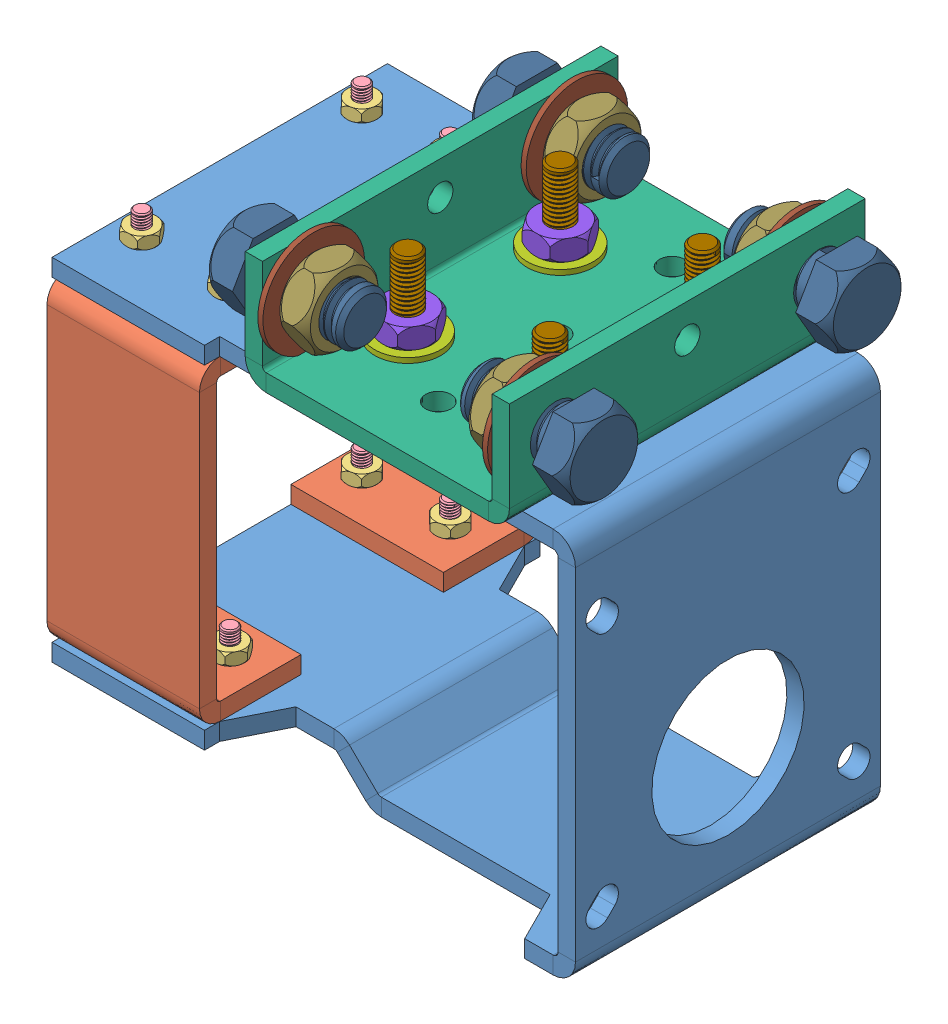
SolidWorks assembly Motor Hub Asm, configuration Default. Lengths in mm.
Overall size (108.85 123.96 126.02).
72 component instances, 12 part files, 10 mates.
Components (placement in the parent):
- Main Motor Flange-1: Main Motor Flange [Default] at (107.3541 101.0612 120.121) x (-1 0 0) z (0 0 -1) size (100 80 66)
- Side Flange x2-1: Side Flange x2 [Default] at (37.3541 66.5612 124.121) x (0 0 1) z (-1 0 0) size (20 62.2 30)
- Screw 3mm total Asm-1: Screw 3mm total Asm [Default] at (21.6788 105.6065 99.6182) x (0.996489 0 0.083719) z (-0.083719 0 0.996489) size (8.57 15.29 8.76)
  - Nut 3 mm-1: Nut 3 mm [Default] at (-6.9703 -2.6351 12.8014) x (0.355877 0 -0.934533) z (0.934533 0 0.355877) size (6.87 2.69 6.56)
  - Screw 3mm-1: Screw 3mm [Default] at (-6.97 -14.6573 12.8027) x (0 0 -1) z (-1 0 0) size (6 15.29 6)
  - Ross 3 mm-1: Ross 3 mm [Default] at (-6.9707 -11.1453 12.802) size (7.8 0.6 7.8)
- Screw 3mm total Asm-2: Screw 3mm total Asm [Default] at (16.5317 105.6065 110.4602) x (-0.395991 0 -0.918254) z (0.918254 0 -0.395991) size (8.57 15.29 8.76)
  - Nut 3 mm-1: Nut 3 mm [Default] at (-6.9703 -2.6351 12.8014) x (0.355877 0 -0.934533) z (0.934533 0 0.355877) size (6.87 2.69 6.56)
  - Screw 3mm-1: Screw 3mm [Default] at (-6.97 -14.6573 12.8027) x (0 0 -1) z (-1 0 0) size (6 15.29 6)
  - Ross 3 mm-1: Ross 3 mm [Default] at (-6.9707 -11.1453 12.802) size (7.8 0.6 7.8)
- Screw 3mm total Asm-13: Screw 3mm total Asm [Default] at (40.0426 105.6065 79.9207) x (-0.395991 0 0.918254) z (-0.918254 0 -0.395991) size (8.57 15.29 8.76)
  - Nut 3 mm-1: Nut 3 mm [Default] at (-6.9703 -2.6351 12.8014) x (0.355877 0 -0.934533) z (0.934533 0 0.355877) size (6.87 2.69 6.56)
  - Screw 3mm-1: Screw 3mm [Default] at (-6.97 -14.6573 12.8027) x (0 0 -1) z (-1 0 0) size (6 15.29 6)
  - Ross 3 mm-1: Ross 3 mm [Default] at (-6.9707 -11.1453 12.802) size (7.8 0.6 7.8)
- Screw 3mm total Asm-15: Screw 3mm total Asm [Default] at (19.5352 105.6065 55.1098) x (0.996489 0 -0.083719) z (0.083719 0 0.996489) size (8.57 15.29 8.76)
  - Nut 3 mm-1: Nut 3 mm [Default] at (-6.9703 -2.6351 12.8014) x (0.355877 0 -0.934533) z (0.934533 0 0.355877) size (6.87 2.69 6.56)
  - Screw 3mm-1: Screw 3mm [Default] at (-6.97 -14.6573 12.8027) x (0 0 -1) z (-1 0 0) size (6 15.29 6)
  - Ross 3 mm-1: Ross 3 mm [Default] at (-6.9707 -11.1453 12.802) size (7.8 0.6 7.8)
- Side Flange x2-2: Side Flange x2 [Default] at (7.3541 66.5612 56.121) x (0 0 -1) z (1 0 0) size (20 62.2 30)
- Upper Flange-1: Upper Flange [Default] at (73.3541 101.0612 55.121) x (0 -1 0) z (0 0 1) size (22 52 70)
- Screw 3mm total Asm-19: Screw 3mm total Asm [Default] at (16.5317 43.4065 110.4602) x (-0.395991 0 -0.918254) z (0.918254 0 -0.395991) size (8.57 15.29 8.76)
  - Nut 3 mm-1: Nut 3 mm [Default] at (-6.9703 -2.6351 12.8014) x (0.355877 0 -0.934533) z (0.934533 0 0.355877) size (6.87 2.69 6.56)
  - Screw 3mm-1: Screw 3mm [Default] at (-6.97 -14.6573 12.8027) x (0 0 -1) z (-1 0 0) size (6 15.29 6)
  - Ross 3 mm-1: Ross 3 mm [Default] at (-6.9707 -11.1453 12.802) size (7.8 0.6 7.8)
- Screw 3mm total Asm-20: Screw 3mm total Asm [Default] at (21.6788 43.4065 99.6182) x (0.996489 0 0.083719) z (-0.083719 0 0.996489) size (8.57 15.29 8.76)
  - Nut 3 mm-1: Nut 3 mm [Default] at (-6.9703 -2.6351 12.8014) x (0.355877 0 -0.934533) z (0.934533 0 0.355877) size (6.87 2.69 6.56)
  - Screw 3mm-1: Screw 3mm [Default] at (-6.97 -14.6573 12.8027) x (0 0 -1) z (-1 0 0) size (6 15.29 6)
  - Ross 3 mm-1: Ross 3 mm [Default] at (-6.9707 -11.1453 12.802) size (7.8 0.6 7.8)
- Screw 3mm total Asm-21: Screw 3mm total Asm [Default] at (40.0426 43.4065 79.9207) x (-0.395991 0 0.918254) z (-0.918254 0 -0.395991) size (8.57 15.29 8.76)
  - Nut 3 mm-1: Nut 3 mm [Default] at (-6.9703 -2.6351 12.8014) x (0.355877 0 -0.934533) z (0.934533 0 0.355877) size (6.87 2.69 6.56)
  - Screw 3mm-1: Screw 3mm [Default] at (-6.97 -14.6573 12.8027) x (0 0 -1) z (-1 0 0) size (6 15.29 6)
  - Ross 3 mm-1: Ross 3 mm [Default] at (-6.9707 -11.1453 12.802) size (7.8 0.6 7.8)
- Screw 3mm total Asm-22: Screw 3mm total Asm [Default] at (19.5352 43.4065 55.1098) x (0.996489 0 -0.083719) z (0.083719 0 0.996489) size (8.57 15.29 8.76)
  - Nut 3 mm-1: Nut 3 mm [Default] at (-6.9703 -2.6351 12.8014) x (0.355877 0 -0.934533) z (0.934533 0 0.355877) size (6.87 2.69 6.56)
  - Screw 3mm-1: Screw 3mm [Default] at (-6.97 -14.6573 12.8027) x (0 0 -1) z (-1 0 0) size (6 15.29 6)
  - Ross 3 mm-1: Ross 3 mm [Default] at (-6.9707 -11.1453 12.802) size (7.8 0.6 7.8)
- Screw 5mm total Asm - Short-1: Screw 5mm total Asm - Short [Default] at (63.5617 84.1105 53.2245) x (-1 0 0) z (0 0 1) size (13.87 25.49 13.87)
  - Ross 5 mm-1: Ross 5 mm [Default] at (4.2075 -20.4507 21.8965) x (0.997618 0 0.068982) z (-0.068982 0 0.997618) size (13 1 13)
  - Nut 5 mm-1: Nut 5 mm [Default] at (4.2075 -23.4507 21.8965) size (11.46 4.49 10.93)
  - Screw 5mm - short-1: Screw 5mm - short [Default] at (4.2075 -13.2778 21.8965) size (10 25.49 10)
- Screw 5mm total Asm - Short-2: Screw 5mm total Asm - Short [Default] at (63.5617 84.1105 83.2245) x (-1 0 0) z (0 0 1) size (13.87 25.49 13.87)
  - Ross 5 mm-1: Ross 5 mm [Default] at (4.2075 -20.4507 21.8965) x (0.997618 0 0.068982) z (-0.068982 0 0.997618) size (13 1 13)
  - Nut 5 mm-1: Nut 5 mm [Default] at (4.2075 -23.4507 21.8965) size (11.46 4.49 10.93)
  - Screw 5mm - short-1: Screw 5mm - short [Default] at (4.2075 -13.2778 21.8965) size (10 25.49 10)
- Screw 5mm total Asm - Short-3: Screw 5mm total Asm - Short [Default] at (83.1466 84.1105 127.0175) x (1 0 0) z (0 0 -1) size (13.87 25.49 13.87)
  - Ross 5 mm-1: Ross 5 mm [Default] at (4.2075 -20.4507 21.8965) x (0.997618 0 0.068982) z (-0.068982 0 0.997618) size (13 1 13)
  - Nut 5 mm-1: Nut 5 mm [Default] at (4.2075 -23.4507 21.8965) size (11.46 4.49 10.93)
  - Screw 5mm - short-1: Screw 5mm - short [Default] at (4.2075 -13.2778 21.8965) size (10 25.49 10)
- Screw 5mm total Asm - Short-4: Screw 5mm total Asm - Short [Default] at (83.1466 84.1105 97.0175) x (1 0 0) z (0 0 -1) size (13.87 25.49 13.87)
  - Ross 5 mm-1: Ross 5 mm [Default] at (4.2075 -20.4507 21.8965) x (0.997618 0 0.068982) z (-0.068982 0 0.997618) size (13 1 13)
  - Nut 5 mm-1: Nut 5 mm [Default] at (4.2075 -23.4507 21.8965) size (11.46 4.49 10.93)
  - Screw 5mm - short-1: Screw 5mm - short [Default] at (4.2075 -13.2778 21.8965) size (10 25.49 10)
- Connection Bolt 10mm Asm-1: Connection Bolt 10mm Asm [Default] at (38.4349 133.6325 65.0322) x (0 0 -1) z (0 -1 0) size (20 24 20)
  - Connection Bolt 10mm-1: Connection Bolt 10mm [Default] at (0.8074 7.1628 19.6751) size (16.81 24 16.17)
  - Assem1^Connection Bolt 10mm Asm-1: Assem1^Connection Bolt 10mm Asm [Default] at origin (virtual)
  - Ross 10 mm-1: Ross 10 mm [Default] at (0.8112 13.3192 19.6713) size (20 1 20)
  - Nut 10 mm-1: Nut 10 mm [Default] at (0.7979 16.3164 19.6624) x (-1 0 0) z (0 0 1) size (16.81 6 16.17)
- Connection Bolt 10mm Asm-2: Connection Bolt 10mm Asm [Default] at (38.4349 94.2899 115.2098) x (0 0 1) z (0 1 0) size (20 24 20)
  - Connection Bolt 10mm-1: Connection Bolt 10mm [Default] at (0.8074 7.1628 19.6751) size (16.81 24 16.17)
  - Assem1^Connection Bolt 10mm Asm-1: Assem1^Connection Bolt 10mm Asm [Default] at origin (virtual)
  - Ross 10 mm-1: Ross 10 mm [Default] at (0.8112 13.3192 19.6713) size (20 1 20)
  - Nut 10 mm-1: Nut 10 mm [Default] at (0.7979 16.3164 19.6624) x (-1 0 0) z (0 0 1) size (16.81 6 16.17)
- Connection Bolt 10mm Asm-3: Connection Bolt 10mm Asm [Default] at (108.2733 94.2899 65.0322) x (0 0 -1) z (0 1 0) size (20 24 20)
  - Connection Bolt 10mm-1: Connection Bolt 10mm [Default] at (0.8074 7.1628 19.6751) size (16.81 24 16.17)
  - Assem1^Connection Bolt 10mm Asm-1: Assem1^Connection Bolt 10mm Asm [Default] at origin (virtual)
  - Ross 10 mm-1: Ross 10 mm [Default] at (0.8112 13.3192 19.6713) size (20 1 20)
  - Nut 10 mm-1: Nut 10 mm [Default] at (0.7979 16.3164 19.6624) x (-1 0 0) z (0 0 1) size (16.81 6 16.17)
- Connection Bolt 10mm Asm-4: Connection Bolt 10mm Asm [Default] at (108.2733 133.6325 115.2098) x (0 0 1) z (0 -1 0) size (20 24 20)
  - Connection Bolt 10mm-1: Connection Bolt 10mm [Default] at (0.8074 7.1628 19.6751) size (16.81 24 16.17)
  - Assem1^Connection Bolt 10mm Asm-1: Assem1^Connection Bolt 10mm Asm [Default] at origin (virtual)
  - Ross 10 mm-1: Ross 10 mm [Default] at (0.8112 13.3192 19.6713) size (20 1 20)
  - Nut 10 mm-1: Nut 10 mm [Default] at (0.7979 16.3164 19.6624) x (-1 0 0) z (0 0 1) size (16.81 6 16.17)
Mates (geometry in assembly coordinates):
- Coincident4: coincident aligned: circle of Main Motor Flange-1; circle of Side Flange x2-1
- Coincident5: coincident aligned: circle of Main Motor Flange-1; circle of Side Flange x2-1
- Concentric4: concentric anti-aligned: circle of Side Flange x2-1; circle of Screw 3mm total Asm-1/Ross 3 mm-1
- Concentric5: concentric aligned: circle of Side Flange x2-1; circle of Screw 3mm total Asm-2/Ross 3 mm-1
- Coincident7: coincident anti-aligned: plane of Side Flange x2-1 through (37.3541 94.2612 124.121) normal (0 -1 0); plane of Screw 3mm total Asm-2/Ross 3 mm-1 through (31.0475 94.2612 111.7916) normal (0 1 0)
- Coincident20: coincident aligned: circle of Main Motor Flange-1; circle of Upper Flange-1
- Coincident21: coincident aligned: circle of Main Motor Flange-1; circle of Upper Flange-1
- Coincident23: coincident anti-aligned: plane of Side Flange x2-1 through (37.3541 94.2612 124.121) normal (0 -1 0); plane of Screw 3mm total Asm-1/Ross 3 mm-1 through (13.6608 94.2612 111.7916) normal (0 1 0)
- Coincident24: coincident anti-aligned: circle of Main Motor Flange-1; circle of Screw 5mm total Asm - Short-1/Screw 5mm - short-1
- Coincident25: coincident aligned: circle of Upper Flange-1; circle of Connection Bolt 10mm Asm-1/Ross 10 mm-1
